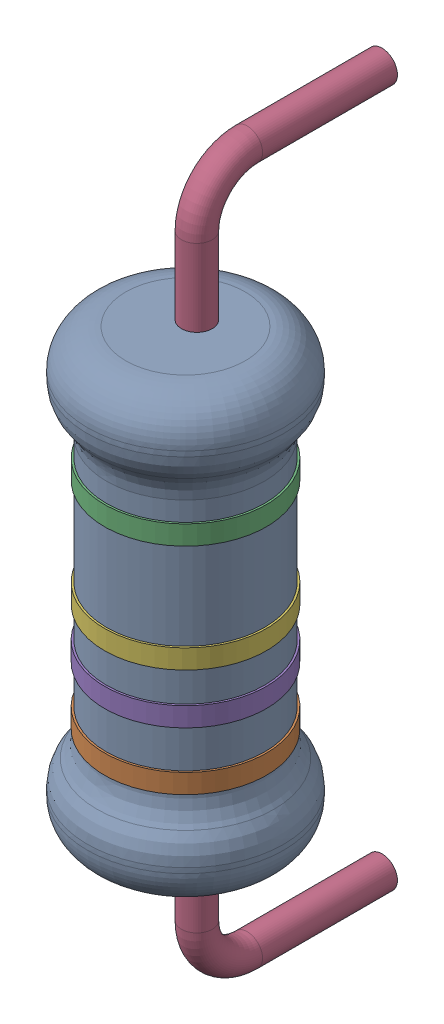
SolidWorks assembly R6.step, configuration Default. Lengths in mm.
Overall size (5.72 18.91 7.96).
7 component instances, 6 part files, 0 mates.
Components (placement in the parent):
- Res_Yageo_KNP100JR-73-22R_eec.step-1: Res_Yageo_KNP100JR-73-22R_eec.step [Default] at (45.974 17.653 0) x (0 1 0) z (0 0 1) size (18.91 5.72 7.96)
  - 1.step-1: 1.step [Default] at (0 0 2.55) size (11.5 5.1 5.1)
  - 2.step-1: 2.step [Default] at (-3.2931 0 2.55) x (0 0 -1) z (1 0 0) size (4.2 4.2 0.5)
  - 3.step-1: 3.step [Default] at (2.7931 0 2.55) x (0 -0.492137 0.870518) z (-1 0 0) size (4.2 4.2 0.5)
  - 4.step-1: 4.step [Default] at (0 0 -2.55) size (18.91 0.8 5.21)
  - 5.step-1: 5.step [Default] at (-1.7931 0 2.55) x (0 0 -1) z (1 0 0) size (4.2 4.2 0.5)
  - 6.step-1: 6.step [Default] at (0.0069 0 2.55) x (0 -0.017206 0.999852) z (-1 0 0) size (4.2 4.2 0.5)
